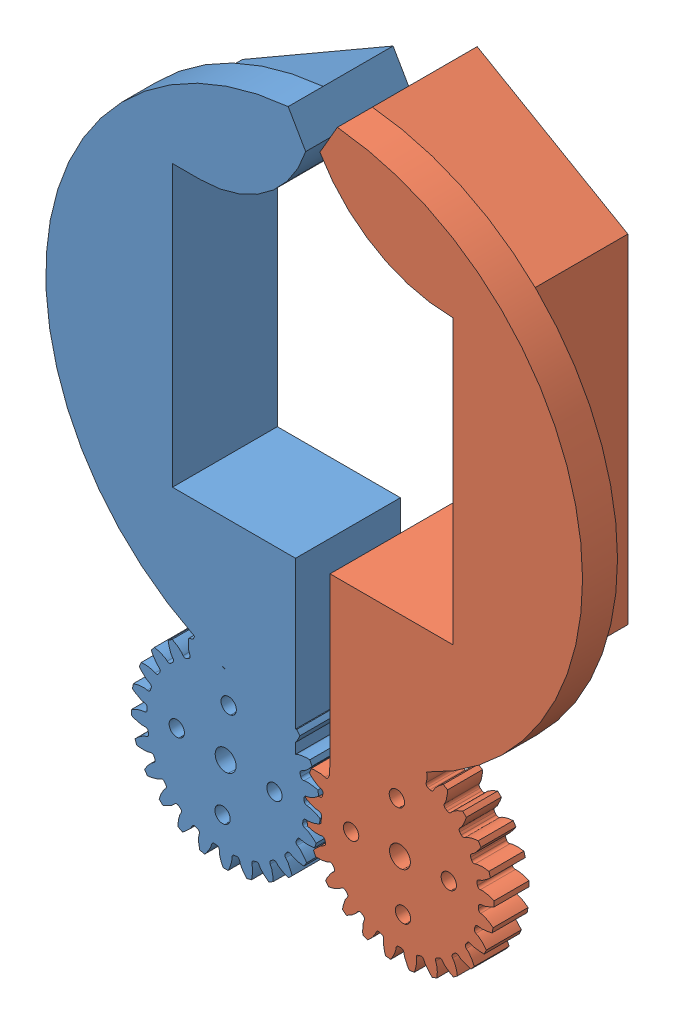
SolidWorks assembly 手臂ver1, configuration 默认. Lengths in mm.
Overall size (76.61 99.7 20.18).
2 component instances, 2 part files, 0 mates.
Components (placement in the parent):
- 左臂直齿M1X25-1: 左臂直齿M1X25 [M1X25] at (-90.8185 -69.0725 4.9439) size (39.22 98.93 15)
- 右臂直齿M1X25-1: 右臂直齿M1X25 [M1X25] at (-66.0592 -68.7076 9.7671) x (-1 0 0) z (0 0 -1) size (39.61 99.26 20)
